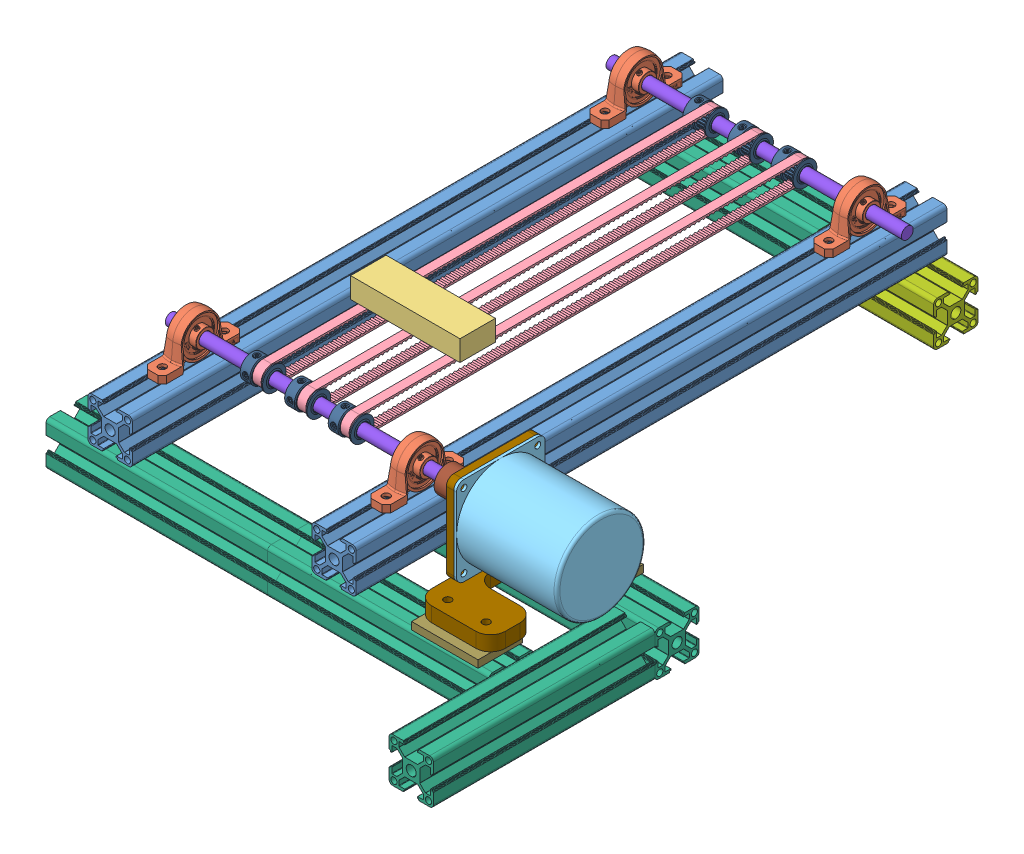
SolidWorks assembly Conveyor_Assembly, configuration Default. Lengths in mm.
Overall size (330 105 467.75).
29 component instances, 12 part files, 57 mates.
Components (placement in the parent):
- Perfil aluminio 30 x 30 x 400-1: Perfil aluminio 30 x 30 x 400 [Predeterminado] at (152.8852 266.7682 265.725) size (30 30 400)
- Perfil aluminio 30 x 30 x 400-2: Perfil aluminio 30 x 30 x 400 [Predeterminado] at (304.4852 266.7682 265.725) size (30 30 400)
- Pillow Block P08-1: Pillow Block P08 [Default] at (153.3852 296.7682 260.2119) x (0 0 -1) z (1 0 0) size (55 39.88 14.5)
- Pillow Block P08-4: Pillow Block P08 [Default] at (304.9852 296.7682 260.2119) x (0 0 -1) z (1 0 0) size (55 39.88 14.5)
- Pillow Block P08-5: Pillow Block P08 [Default] at (304.9852 296.7682 559.8617) x (0 0 -1) z (1 0 0) size (55 39.88 14.5)
- Pillow Block P08-6: Pillow Block P08 [Default] at (153.3852 296.7682 559.8617) x (0 0 -1) z (1 0 0) size (55 39.88 14.5)
- Object-1: Object [Default] at (232.9362 304.965 483.9278) x (-1 0 0) z (0 0 -1) size (74 14 24)
- Timing Belt-2: Timing Belt [Default] at (206.5683 297.2875 259.9346) x (0 0 1) z (-1 0 0) size (314.4 14.4 6)
- Timing Belt-3: Timing Belt [Default] at (236.8068 297.2773 259.9263) x (0 0 1) z (-1 0 0) size (314.4 14.4 6)
- Timing Belt-4: Timing Belt [Default] at (266.099 297.2863 259.9028) x (0 0 1) z (-1 0 0) size (314.4 14.4 6)
- Motor-1: Motor [Default] at (429.5689 296.7682 559.8617) x (0 0 -1) z (-1 0 0) size (60 60 89)
- Perfil aluminio 30 x 30 x 100-1: Perfil aluminio 30 x 30 x 100 [Predeterminado] at (639.4852 236.7682 518.4744) x (0 0 1) z (-1 0 0) size (30 30 150)
- Perfil aluminio 30 x 30 x 100-2: Perfil aluminio 30 x 30 x 100 [Predeterminado] at (609.4852 236.7682 600.725) x (0 0 1) z (-1 0 0) size (30 30 150)
- Perfil aluminio 30 x 30 x 100-3: Perfil aluminio 30 x 30 x 100 [Predeterminado] at (459.4852 236.7682 600.725) x (0 0 1) z (-1 0 0) size (30 30 150)
- Perfil aluminio 30 x 30 x 100-4: Perfil aluminio 30 x 30 x 100 [Predeterminado] at (-89.5478 236.7682 230.725) x (0 0 -1) z (1 0 0) size (30 30 150)
- Perfil aluminio 30 x 30 x 80-1: Perfil aluminio 30 x 30 x 80 [Predeterminado] at (310.4522 236.7682 230.725) x (0 0 -1) z (1 0 0) size (30 30 80)
- Perfil aluminio 30 x 30 x 100-7: Perfil aluminio 30 x 30 x 100 [Predeterminado] at (424.4852 236.7682 333.4744) size (30 30 150)
- Shaft-3: Shaft [Default] at (338.3567 296.7682 559.8617) x (0 0.974547 0.224185) z (-1 0 0) size (8 8 200)
- Motor Support-1: Motor Support [Default] at (354.6841 296.7682 559.8617) x (0 1 0) z (1 0 0) size (70 100 50)
- Shaft-4: Shaft [Default] at (337.0919 296.7682 260.2119) x (0 0.679401 -0.733767) z (-1 0 0) size (8 8 200)
- GT2_20T-sh8-1: GT2_20T-sh8 [Конфигурация1] at (192.6352 296.7682 559.8617) x (1 0 0) z (0 -0.035771 0.99936) size (16 16 16)
- GT2_20T-sh8-2: GT2_20T-sh8 [Конфигурация1] at (222.7529 296.7682 559.8617) size (16 16 16)
- GT2_20T-sh8-3: GT2_20T-sh8 [Конфигурация1] at (252.2364 296.7682 559.8617) size (16 16 16)
- GT2_20T-sh8-4: GT2_20T-sh8 [Конфигурация1] at (192.6577 296.7682 260.2119) x (1 0 0) z (0 -0.070557 0.997508) size (16 16 16)
- GT2_20T-sh8-5: GT2_20T-sh8 [Конфигурация1] at (222.8247 296.7682 260.2119) x (1 0 0) z (0 -0.181155 0.983455) size (16 16 16)
- GT2_20T-sh8-6: GT2_20T-sh8 [Конфигурация1] at (252.2243 296.7682 260.2119) x (1 0 0) z (0 -0.038932 0.999242) size (16 16 16)
- 5X8_COUPLER-1: 5X8_COUPLER [Default] at (337.8783 296.7682 559.8617) x (0 0.949441 0.313944) z (0 -0.313944 0.949441) size (18.22 25 18.22)
- Filler piece-1: Filler piece [Default] at (379.6171 251.7682 600.8617) x (0 0 1) z (0 1 0) size (30 45 5)
- Filler piece-2: Filler piece [Default] at (379.6171 251.7682 518.8617) x (0 0 1) z (0 1 0) size (30 45 5)
Mates (geometry in assembly coordinates):
- Distance1: distance = 140 mm anti-aligned: plane of Perfil aluminio 30 x 30 x 400-1 through (158.6852 271.0289 615.725) normal (1 0 0); plane of Perfil aluminio 30 x 30 x 400-2 through (298.6852 262.5065 615.725) normal (-1 0 0)
- Parallel2: parallel anti-aligned: plane of Perfil aluminio 30 x 30 x 400-1 through (158.6852 271.0289 615.725) normal (1 0 0); plane of Perfil aluminio 30 x 30 x 400-2 through (298.6852 262.5065 615.725) normal (-1 0 0)
- Coincident3: coincident aligned: plane of Perfil aluminio 30 x 30 x 400-1 through (158.2852 281.7682 615.725) normal (0 1 0); plane of Perfil aluminio 30 x 30 x 400-2 through (291.9852 281.7682 615.725) normal (0 1 0)
- Coincident4: coincident aligned: plane of Perfil aluminio 30 x 30 x 400-1 through (138.1852 261.3682 615.725) normal (0 0 1); plane of Perfil aluminio 30 x 30 x 400-2 through (289.7852 261.3682 615.725) normal (0 0 1)
- Parallel3: parallel aligned: plane of Perfil aluminio 30 x 30 x 400-1 through (138.1852 261.3682 615.725) normal (0 0 1); plane of Pillow Block P08-1 through (159.8852 296.7682 287.7119) normal (0 0 1)
- Coincident10: coincident anti-aligned: plane of Perfil aluminio 30 x 30 x 400-1 through (140.3852 281.7682 615.725) normal (0 1 0); plane of Pillow Block P08-1 through (153.3852 281.7682 260.2119) normal (0 -1 0)
- Distance3: distance = 8 mm aligned: plane of Perfil aluminio 30 x 30 x 400-1 through (167.8852 279.2682 615.725) normal (1 0 0); plane of Pillow Block P08-1 through (159.8852 296.7682 260.2119) normal (1 0 0)
- Distance4: distance = 8 mm aligned: plane of Pillow Block P08-4 through (311.4852 296.7682 260.2119) normal (1 0 0); plane of Perfil aluminio 30 x 30 x 400-2 through (319.4852 279.2682 615.725) normal (1 0 0)
- Coincident13: coincident anti-aligned: plane of Perfil aluminio 30 x 30 x 400-2 through (309.8852 281.7682 615.725) normal (0 1 0); plane of Pillow Block P08-4 through (304.9852 281.7682 260.2119) normal (0 -1 0)
- Parallel6: parallel aligned: plane of Perfil aluminio 30 x 30 x 400-2 through (289.7852 261.3682 615.725) normal (0 0 1); plane of Pillow Block P08-4 through (311.4852 296.7682 287.7119) normal (0 0 1)
- Concentric1: concentric aligned: cylinder of Pillow Block P08-1 through (145.148 296.7682 260.2119) axis (-1 0 0) radius 4; cylinder of Pillow Block P08-4 through (296.748 296.7682 260.2119) axis (-1 0 0) radius 4
- Concentric3: concentric aligned: cylinder of Pillow Block P08-5 through (296.748 296.7682 559.8617) axis (-1 0 0) radius 4; cylinder of Pillow Block P08-6 through (145.148 296.7682 559.8617) axis (-1 0 0) radius 4
- Parallel7: parallel aligned: plane of Perfil aluminio 30 x 30 x 400-1 through (138.1852 261.3682 615.725) normal (0 0 1); plane of Pillow Block P08-6 through (159.8852 296.7682 587.3617) normal (0 0 1)
- Distance9: distance = 8 mm aligned: plane of Perfil aluminio 30 x 30 x 400-1 through (167.8852 279.2682 615.725) normal (1 0 0); plane of Pillow Block P08-6 through (159.8852 296.7682 559.8617) normal (1 0 0)
- Coincident18: coincident anti-aligned: plane of Perfil aluminio 30 x 30 x 400-1 through (158.2852 281.7682 615.725) normal (0 1 0); plane of Pillow Block P08-6 through (153.3852 281.7682 559.8617) normal (0 -1 0)
- Distance7: distance = 8 mm aligned: plane of Pillow Block P08-5 through (311.4852 296.7682 559.8617) normal (1 0 0); plane of Perfil aluminio 30 x 30 x 400-2 through (319.4852 279.2682 615.725) normal (1 0 0)
- Coincident20: coincident anti-aligned: plane of Perfil aluminio 30 x 30 x 400-2 through (309.8852 281.7682 615.725) normal (0 1 0); plane of Pillow Block P08-5 through (304.9852 281.7682 559.8617) normal (0 -1 0)
- Parallel9: parallel aligned: plane of Perfil aluminio 30 x 30 x 400-2 through (289.7852 261.3682 615.725) normal (0 0 1); plane of Pillow Block P08-5 through (311.4852 296.7682 587.3617) normal (0 0 1)
- Parallel11: parallel anti-aligned: plane of Perfil aluminio 30 x 30 x 400-1 through (158.2852 281.7682 615.725) normal (0 1 0); plane of Object-1 through (232.9362 304.965 483.9278) normal (0 -1 0)
- Perpendicular2: perpendicular: plane of Perfil aluminio 30 x 30 x 400-1 through (138.1852 261.3682 615.725) normal (0 0 1); plane of Object-1 through (269.9362 318.965 495.9278) normal (1 0 0)
- Parallel28: parallel anti-aligned: plane of Perfil aluminio 30 x 30 x 400-1 through (167.8852 261.3682 615.725) normal (1 0 0); plane of Timing Belt-2 through (200.5683 297.2875 259.9346) normal (-1 0 0)
- Parallel29: parallel aligned: plane of Perfil aluminio 30 x 30 x 400-2 through (309.8852 281.7682 615.725) normal (0 1 0); plane of Motor-1 through (359.5689 326.7682 534.8617) normal (0 1 0)
- Coincident49: coincident aligned: plane of Perfil aluminio 30 x 30 x 100-2 through (259.4852 251.7682 588.225) normal (0 1 0); plane of Perfil aluminio 30 x 30 x 100-3 through (109.4852 251.7682 588.225) normal (0 1 0)
- Coincident50: coincident anti-aligned: plane of Perfil aluminio 30 x 30 x 100-2 through (259.4852 231.3682 586.025) normal (-1 0 0); plane of Perfil aluminio 30 x 30 x 100-3 through (259.4852 236.7682 600.725) normal (1 0 0)
- Coincident52: coincident aligned: plane of Perfil aluminio 30 x 30 x 100-2 through (259.4852 242.1682 585.725) normal (0 0 -1); plane of Perfil aluminio 30 x 30 x 100-3 through (109.4852 242.1682 585.725) normal (0 0 -1)
- Coincident61: coincident aligned: plane of Perfil aluminio 30 x 30 x 400-1 through (138.1852 261.3682 615.725) normal (0 0 1); plane of Perfil aluminio 30 x 30 x 100-3 through (109.4852 249.2682 615.725) normal (0 0 1)
- Coincident58: coincident anti-aligned: plane of Perfil aluminio 30 x 30 x 400-1 through (165.3852 251.7682 615.725) normal (0 -1 0); plane of Perfil aluminio 30 x 30 x 100-2 through (259.4852 251.7682 588.225) normal (0 1 0)
- Coincident62: coincident aligned: plane of Perfil aluminio 30 x 30 x 400-2 through (289.7852 261.3682 215.725) normal (0 0 -1); plane of Perfil aluminio 30 x 30 x 100-4 through (260.4522 249.2682 215.725) normal (0 0 -1)
- Coincident64: coincident anti-aligned: plane of Perfil aluminio 30 x 30 x 400-1 through (147.4852 251.7682 615.725) normal (0 -1 0); plane of Perfil aluminio 30 x 30 x 100-4 through (260.4522 251.7682 243.225) normal (0 1 0)
- Parallel42: parallel aligned: plane of Perfil aluminio 30 x 30 x 400-1 through (137.8852 254.2682 615.725) normal (-1 0 0); plane of Perfil aluminio 30 x 30 x 100-3 through (109.4852 231.3682 586.025) normal (-1 0 0)
- Parallel40: parallel aligned: plane of Perfil aluminio 30 x 30 x 400-1 through (137.8852 254.2682 615.725) normal (-1 0 0); plane of Perfil aluminio 30 x 30 x 100-4 through (110.4522 236.7682 230.725) normal (-1 0 0)
- Parallel43: parallel aligned: plane of Perfil aluminio 30 x 30 x 400-2 through (289.4852 254.2682 615.725) normal (-1 0 0); plane of Perfil aluminio 30 x 30 x 100-1 through (289.4852 231.3682 503.7744) normal (-1 0 0)
- Coincident73: coincident anti-aligned: plane of Perfil aluminio 30 x 30 x 400-2 through (316.9852 251.7682 615.725) normal (0 -1 0); plane of Perfil aluminio 30 x 30 x 100-1 through (289.4852 251.7682 523.8744) normal (0 1 0)
- Coincident74: coincident aligned: plane of Perfil aluminio 30 x 30 x 400-2 through (289.4852 254.2682 615.725) normal (-1 0 0); plane of Perfil aluminio 30 x 30 x 100-1 through (289.4852 231.3682 503.7744) normal (-1 0 0)
- Coincident76: coincident anti-aligned: plane of Perfil aluminio 30 x 30 x 100-4 through (260.4522 231.3682 245.425) normal (1 0 0); plane of Perfil aluminio 30 x 30 x 80-1 through (260.4522 231.3682 245.425) normal (-1 0 0)
- Coincident77: coincident aligned: plane of Perfil aluminio 30 x 30 x 100-4 through (260.4522 251.7682 225.325) normal (0 1 0); plane of Perfil aluminio 30 x 30 x 80-1 through (660.4522 251.7682 225.325) normal (0 1 0)
- Coincident78: coincident aligned: plane of Perfil aluminio 30 x 30 x 100-4 through (260.4522 249.2682 215.725) normal (0 0 -1); plane of Perfil aluminio 30 x 30 x 80-1 through (660.4522 249.2682 215.725) normal (0 0 -1)
- Coincident82: coincident anti-aligned: plane of Perfil aluminio 30 x 30 x 100-2 through (409.4852 236.7682 600.725) normal (1 0 0); plane of Perfil aluminio 30 x 30 x 100-7 through (409.4852 242.1682 683.4744) normal (-1 0 0)
- Coincident83: coincident anti-aligned: plane of Perfil aluminio 30 x 30 x 100-1 through (289.4852 249.2682 533.4744) normal (0 0 1); plane of Perfil aluminio 30 x 30 x 100-7 through (424.4852 236.7682 533.4744) normal (0 0 -1)
- Coincident84: coincident aligned: plane of Perfil aluminio 30 x 30 x 100-1 through (439.4852 236.7682 518.4744) normal (1 0 0); plane of Perfil aluminio 30 x 30 x 100-7 through (439.4852 231.3682 683.4744) normal (1 0 0)
- Coincident85: coincident aligned: plane of Perfil aluminio 30 x 30 x 100-1 through (289.4852 251.7682 523.8744) normal (0 1 0); plane of Perfil aluminio 30 x 30 x 100-7 through (429.8852 251.7682 683.4744) normal (0 1 0)
- Concentric4: concentric anti-aligned: cylinder of Pillow Block P08-6 through (145.148 296.7682 559.8617) axis (-1 0 0) radius 4; cylinder of Shaft-3 through (138.3567 296.7682 559.8617) axis (1 0 0) radius 4
- Concentric9: concentric aligned: cylinder of Motor-1 through (340.5689 296.7682 559.8617) axis (1 0 0) radius 3.5; cylinder of Shaft-3 through (138.3567 296.7682 559.8617) axis (1 0 0) radius 4
- Concentric10: concentric anti-aligned: cylinder of Motor-1 through (361.5689 296.7682 559.8617) axis (1 0 0) radius 30; cylinder of Motor Support-1 through (359.6841 296.7682 559.8617) axis (-1 0 0) radius 22.5
- Parallel50: parallel anti-aligned: plane of Perfil aluminio 30 x 30 x 100-2 through (259.4852 251.7682 588.225) normal (0 1 0); plane of Motor Support-1 through (354.6841 256.7682 559.8617) normal (0 -1 0)
- Concentric11: concentric anti-aligned: cylinder of Pillow Block P08-1 through (145.148 296.7682 260.2119) axis (-1 0 0) radius 4; cylinder of Shaft-4 through (137.0919 296.7682 260.2119) axis (1 0 0) radius 4
- Concentric12: concentric aligned: cylinder of Shaft-3 through (138.3567 296.7682 559.8617) axis (1 0 0) radius 4; cylinder of GT2_20T-sh8-1 through (192.6352 296.7682 559.8617) axis (1 0 0) radius 4
- Concentric13: concentric aligned: cylinder of Shaft-3 through (138.3567 296.7682 559.8617) axis (1 0 0) radius 4; cylinder of GT2_20T-sh8-2 through (222.7529 296.7682 559.8617) axis (1 0 0) radius 4
- Concentric14: concentric aligned: cylinder of Shaft-3 through (138.3567 296.7682 559.8617) axis (1 0 0) radius 4; cylinder of GT2_20T-sh8-3 through (252.2364 296.7682 559.8617) axis (1 0 0) radius 4
- Concentric15: concentric aligned: cylinder of Shaft-4 through (137.0919 296.7682 260.2119) axis (1 0 0) radius 4; cylinder of GT2_20T-sh8-4 through (192.6577 296.7682 260.2119) axis (1 0 0) radius 4
- Concentric16: concentric aligned: cylinder of Shaft-4 through (137.0919 296.7682 260.2119) axis (1 0 0) radius 4; cylinder of GT2_20T-sh8-5 through (222.8247 296.7682 260.2119) axis (1 0 0) radius 4
- Concentric17: concentric aligned: cylinder of Shaft-4 through (137.0919 296.7682 260.2119) axis (1 0 0) radius 4; cylinder of GT2_20T-sh8-6 through (252.2243 296.7682 260.2119) axis (1 0 0) radius 4
- Concentric18: concentric anti-aligned: cylinder of Shaft-3 through (138.3567 296.7682 559.8617) axis (1 0 0) radius 4; cylinder of 5X8_COUPLER-1 through (337.8783 296.7682 559.8617) axis (-1 0 0) radius 4
- Coincident86: coincident anti-aligned: plane of Motor Support-1 through (354.6841 256.7682 559.8617) normal (0 -1 0); plane of Filler piece-1 through (379.6171 256.7682 600.8617) normal (0 1 0)
- Concentric22: concentric anti-aligned: cylinder of Motor Support-1 through (366.6171 256.7682 600.8617) axis (0 1 0) radius 2.5; cylinder of Filler piece-1 through (366.6171 256.7682 600.8617) axis (0 -1 0) radius 4.25
- Coincident88: coincident anti-aligned: plane of Motor Support-1 through (354.6841 256.7682 559.8617) normal (0 -1 0); plane of Filler piece-2 through (379.6171 256.7682 518.8617) normal (0 1 0)
- Concentric23: concentric anti-aligned: cylinder of Motor Support-1 through (366.6171 256.7682 518.8617) axis (0 1 0) radius 2.5; cylinder of Filler piece-2 through (366.6171 256.7682 518.8617) axis (0 -1 0) radius 4.25
